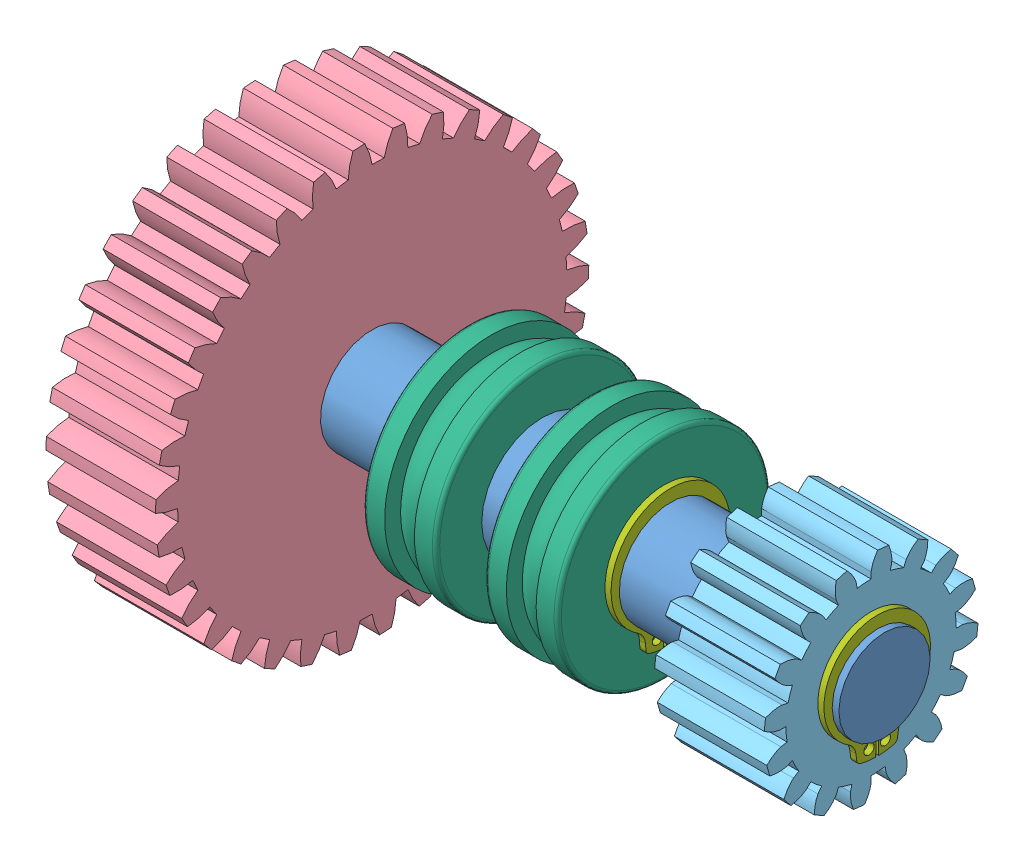
SolidWorks assembly Assem1, configuration Default. Lengths in mm.
Overall size (104.1 77.47 71.2).
11 component instances, 7 part files, 24 mates.
Components (placement in the parent):
- shaft sade-1: shaft sade [Default] at (-22.9713 10.5415 4.9599) size (104.1 20 20)
- charkhhdande chap sade-1: charkhhdande chap sade [Default] at (-63.1213 16.0415 4.9599) x (0 0 -1) z (1 0 0) size (4 4 8)
- charkhhdande rast sade-1: charkhhdande rast sade [Default] at (8.8787 17.5415 4.9599) x (0 0 -1) z (1 0 0) size (5 5 6)
- sade-pele 1 &2-gear-1: sade-pele 1 &2-gear [Default] at (-73.1213 10.5415 4.9599) x (0 0 -1) z (1 0 0) size (71.2 77.47 18)
- sade-pele1 &2-pinion-1: sade-pele1 &2-pinion [Default] at (26.8787 10.5415 4.9599) x (0 0 1) z (-1 0 0) size (35.13 37.28 18)
- thrust ball bearing_68_skf-1: thrust ball bearing_68_skf [SKF - 51203 - 10,SI,NC,10_68] at (-33.1213 10.5415 4.9599) x (1 0 0) z (0 0.105475 0.994422) size (12 35 35)
- thrust ball bearing_68_skf-2: thrust ball bearing_68_skf [SKF - 51203 - 10,SI,NC,10_68] at (-13.1213 10.5415 4.9599) x (1 0 0) z (0 -0.057568 0.998342) size (12 35 35)
- circlip for shafts normal_din-1: circlip for shafts normal_din [Circlip DIN 471 - 12 x 1] at (-73.2213 10.5415 4.9599) x (0 -0.081675 -0.996659) z (1 0 0) size (14.08 16.6 1)
- circlip for shafts normal_din-2: circlip for shafts normal_din [Circlip DIN 471 - 17 x 1] at (-39.2213 10.5415 4.9599) x (0 -0.20176 -0.979435) z (1 0 0) size (19.57 22.3 1)
- circlip for shafts normal_din-3: circlip for shafts normal_din [Circlip DIN 471 - 17 x 1] at (-7.1213 10.5415 4.9599) x (0 0.076574 0.997064) z (-1 0 0) size (19.57 22.3 1)
- circlip for shafts normal_din-4: circlip for shafts normal_din [Circlip DIN 471 - 15 x 1] at (27.8787 10.5415 4.9599) x (0 0 -1) z (1 0 0) size (17.51 20.1 1)
Mates (geometry in assembly coordinates):
- Coincident1: coincident anti-aligned: plane of shaft sade-1 through (-63.1213 14.0415 2.9599) normal (0 0 1); plane of charkhhdande chap sade-1 through (-55.1213 14.0415 2.9599) normal (0 0 -1)
- Coincident2: coincident anti-aligned: plane of shaft sade-1 through (-55.1213 16.5415 4.9599) normal (-1 0 0); plane of charkhhdande chap sade-1 through (-55.1213 16.0415 4.9599) normal (1 0 0)
- Coincident3: coincident anti-aligned: plane of shaft sade-1 through (-63.1213 14.0415 2.9599) normal (0 1 0); plane of charkhhdande chap sade-1 through (-55.1213 14.0415 6.9599) normal (0 -1 0)
- Coincident4: coincident anti-aligned: plane of shaft sade-1 through (14.8787 18.0415 2.4599) normal (0 0 1); plane of charkhhdande rast sade-1 through (14.8787 15.0415 2.4599) normal (0 0 -1)
- Coincident5: coincident anti-aligned: plane of shaft sade-1 through (14.8787 10.5415 4.9599) normal (-1 0 0); plane of charkhhdande rast sade-1 through (14.8787 17.5415 4.9599) normal (1 0 0)
- Coincident6: coincident anti-aligned: plane of shaft sade-1 through (14.8787 15.0415 7.4599) normal (0 1 0); plane of charkhhdande rast sade-1 through (14.8787 15.0415 7.4599) normal (0 -1 0)
- Concentric1: concentric anti-aligned: cylinder of shaft sade-1 through (-75.0213 10.5415 4.9599) axis (-1 0 0) radius 6; cylinder of sade-pele 1 &2-gear-1 through (-73.1213 10.5415 4.9599) axis (1 0 0) radius 6
- Coincident7: coincident anti-aligned: plane of charkhhdande chap sade-1 through (-55.1213 14.0415 2.9599) normal (0 0 -1); plane of sade-pele 1 &2-gear-1 through (-63.1213 16.1984 2.9599) normal (0 0 1)
- Coincident8: coincident anti-aligned: plane of shaft sade-1 through (-55.1213 16.5415 4.9599) normal (-1 0 0); plane of sade-pele 1 &2-gear-1 through (-55.1213 10.5415 4.9599) normal (1 0 0)
- Concentric3: concentric aligned: cylinder of shaft sade-1 through (-75.0213 10.5415 4.9599) axis (-1 0 0) radius 7.5; cylinder of sade-pele1 &2-pinion-1 through (26.8787 10.5415 4.9599) axis (-1 0 0) radius 7.5
- Coincident9: coincident anti-aligned: plane of charkhhdande rast sade-1 through (14.8787 15.0415 7.4599) normal (0 0 1); plane of sade-pele1 &2-pinion-1 through (14.8787 17.6126 7.4599) normal (0 0 -1)
- Coincident10: coincident anti-aligned: plane of shaft sade-1 through (8.8787 19.0415 4.9599) normal (1 0 0); plane of sade-pele1 &2-pinion-1 through (8.8787 10.5415 4.9599) normal (-1 0 0)
- Concentric4: concentric aligned: cylinder of shaft sade-1 through (-75.0213 10.5415 4.9599) axis (-1 0 0) radius 8.5; cylinder of thrust ball bearing_68_skf-1 through (1.8037 10.5415 4.9599) axis (-1 0 0) radius 8.5
- Coincident11: coincident anti-aligned: plane of shaft sade-1 through (-27.1213 19.0415 4.9599) normal (-1 0 0); plane of thrust ball bearing_68_skf-1 through (-27.1213 19.5908 4.0001) normal (1 0 0)
- Concentric5: concentric aligned: cylinder of shaft sade-1 through (-75.0213 10.5415 4.9599) axis (-1 0 0) radius 8.5; cylinder of thrust ball bearing_68_skf-2 through (21.8037 10.5415 4.9599) axis (-1 0 0) radius 8.5
- Coincident12: coincident anti-aligned: plane of shaft sade-1 through (-19.1213 20.5415 4.9599) normal (1 0 0); plane of thrust ball bearing_68_skf-2 through (-19.1213 19.6264 5.4838) normal (-1 0 0)
- Concentric6: concentric anti-aligned: cylinder of shaft sade-1 through (-75.0213 10.5415 4.9599) axis (-1 0 0) radius 5.75; cylinder of circlip for shafts normal_din-1 through (-74.2213 10.5415 4.9599) axis (1 0 0) radius 5.75
- Coincident13: coincident anti-aligned: plane of shaft sade-1 through (-74.2213 16.5415 4.9599) normal (1 0 0); plane of circlip for shafts normal_din-1 through (-74.2213 10.5415 4.9599) normal (-1 0 0)
- Concentric8: concentric anti-aligned: cylinder of shaft sade-1 through (-75.0213 10.5415 4.9599) axis (-1 0 0) radius 8.1; cylinder of circlip for shafts normal_din-2 through (-40.2213 10.5415 4.9599) axis (1 0 0) radius 8.1
- Coincident14: coincident anti-aligned: plane of shaft sade-1 through (-40.2213 19.0415 4.9599) normal (1 0 0); plane of circlip for shafts normal_din-2 through (-40.2213 10.5415 4.9599) normal (-1 0 0)
- Concentric9: concentric aligned: cylinder of shaft sade-1 through (-75.0213 10.5415 4.9599) axis (-1 0 0) radius 8.1; cylinder of circlip for shafts normal_din-3 through (-6.1213 10.5415 4.9599) axis (-1 0 0) radius 8.1
- Coincident15: coincident anti-aligned: plane of shaft sade-1 through (-7.1213 19.0415 4.9599) normal (1 0 0); plane of circlip for shafts normal_din-3 through (-7.1213 10.5415 4.9599) normal (-1 0 0)
- Concentric10: concentric: cylinder of shaft sade-1 through (-75.0213 10.5415 4.9599) axis (-1 0 0) radius 7.15; cylinder of circlip for shafts normal_din-4 through (26.8787 10.5415 4.9599) axis (1 0 0) radius 7.15
- Coincident16: coincident anti-aligned: plane of shaft sade-1 through (26.8787 18.0415 4.9599) normal (1 0 0); plane of circlip for shafts normal_din-4 through (26.8787 10.5415 4.9599) normal (-1 0 0)
